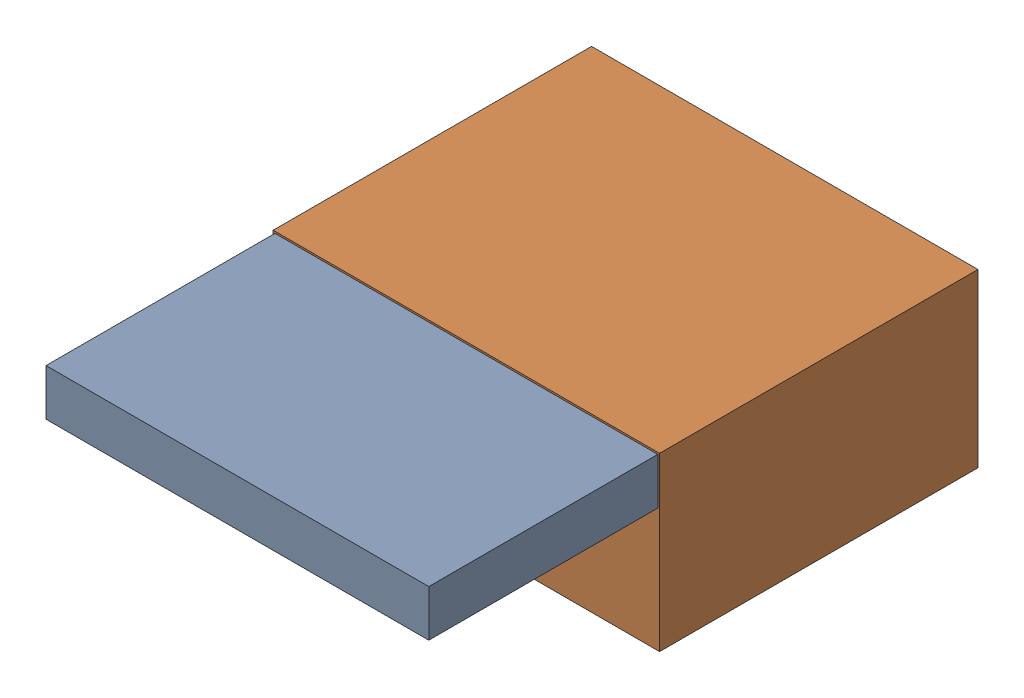
SolidWorks assembly FET-RL_0, configuration Default. Lengths in mm.
Overall size (10.8 4.8 15.3).
4 component instances, 2 part files, 0 mates.
Components (placement in the parent):
- 1017093232-1: 1017093232 [Default] at (73.66 133.01 12.9) size (10.7 1.3 6.4)
  - Extruded-1: Extruded [Default] at origin size (10.7 1.3 6.4)
- 1017093616-1: 1017093616 [Default] at (73.66 131.31 4) size (10.8 4.8 8.9)
  - Extruded_2-1: Extruded_2 [Default] at origin size (10.8 4.8 8.9)
